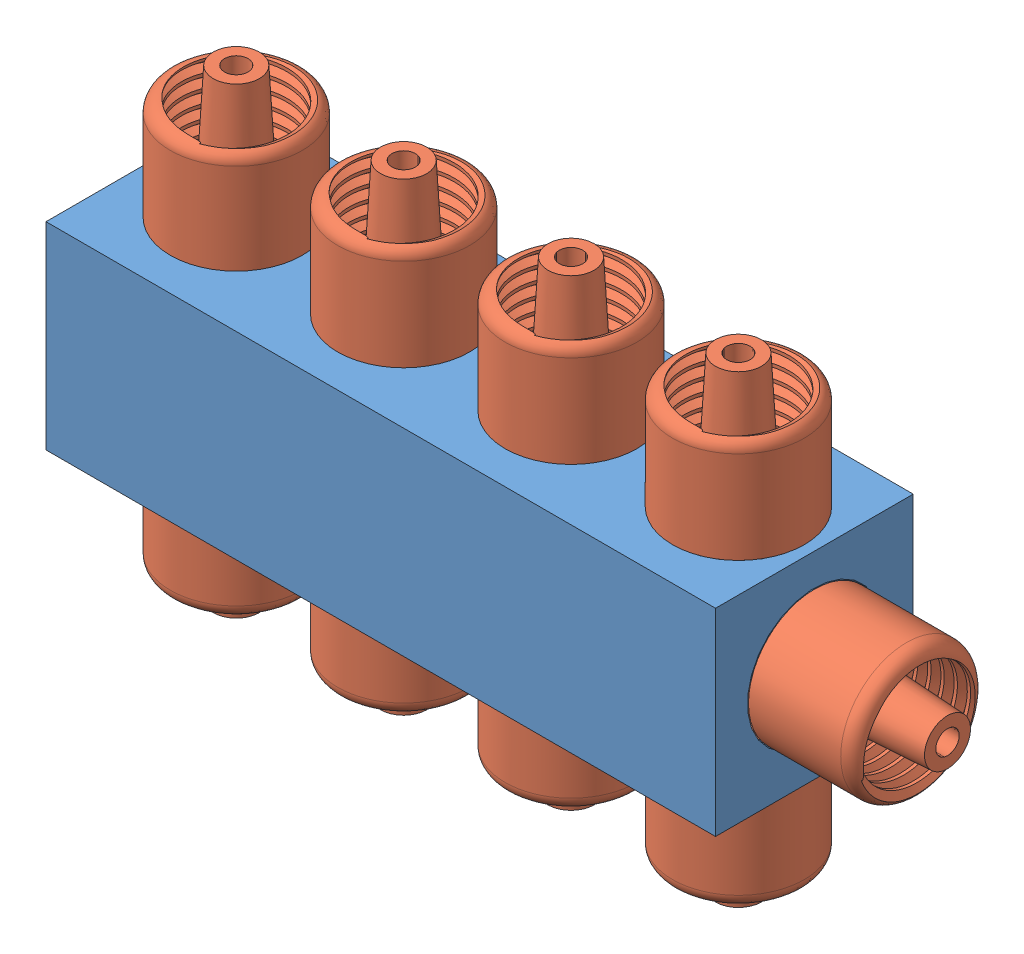
SolidWorks assembly valve_assembly, configuration Default. Lengths in mm.
Overall size (60.9 35.27 15).
10 component instances, 2 part files, 13 mates.
Components (placement in the parent):
- valve_connector-1: valve_connector [Default] at (38.3431 20.2317 33.0319) size (50.8 15 15)
- luer_lock-1: luer_lock [Default] at (32.5797 27.7739 33.0319) size (10 10.1 10)
- luer_lock-2: luer_lock [Default] at (-5.5203 27.6253 33.0319) size (10 10.1 10)
- luer_lock-3: luer_lock [Default] at (7.1797 27.7317 33.0319) size (10 10.1 10)
- luer_lock-4: luer_lock [Default] at (19.8797 27.7317 33.0319) size (10 10.1 10)
- luer_lock-6: luer_lock [Default] at (32.5797 12.7704 33.0319) x (0.999942 0 -0.010804) z (-0.010804 0 -0.999942) size (10 10.1 10)
- luer_lock-7: luer_lock [Default] at (19.8797 12.801 33.0319) x (1 0 0) z (0 0 -1) size (10 10.1 10)
- luer_lock-8: luer_lock [Default] at (7.1797 12.7007 33.0319) x (1 0 0) z (0 0 -1) size (10 10.1 10)
- luer_lock-9: luer_lock [Default] at (-5.5203 12.7317 33.0319) x (0.969422 0 0.2454) z (0.2454 0 -0.969422) size (10 10.1 10)
- luer_lock-10: luer_lock [Default] at (38.3431 20.2317 33.0319) x (0 -1 0) z (0 0 1) size (10 10.1 10)
Mates (geometry in assembly coordinates):
- Concentric1: concentric anti-aligned: circle of valve_connector-1; circle of luer_lock-1
- Concentric2: concentric anti-aligned: circle of valve_connector-1; circle of luer_lock-2
- Concentric3: concentric anti-aligned: circle of valve_connector-1; circle of luer_lock-3
- Concentric4: concentric anti-aligned: circle of valve_connector-1; circle of luer_lock-4
- Concentric8: concentric aligned: circle of valve_connector-1; circle of luer_lock-6
- Concentric9: concentric anti-aligned: cylinder of valve_connector-1; cylinder of luer_lock-6 through (32.5797 4.7704 33.0319) axis (0 1 0) radius 5
- Concentric10: concentric aligned: circle of valve_connector-1; circle of luer_lock-7
- Concentric11: concentric aligned: circle of valve_connector-1; circle of luer_lock-8
- Concentric13: concentric aligned: circle of valve_connector-1; circle of luer_lock-9
- Concentric16: concentric aligned: circle of valve_connector-1; circle of luer_lock-10
- Concentric17: concentric aligned: circle of valve_connector-1; circle of luer_lock-10
- Coincident1: coincident aligned: plane of valve_connector-1 through (38.3431 20.2317 33.0319) normal (1 0 0); circle of luer_lock-10
- Coincident2: coincident aligned: plane of valve_connector-1 through (-12.4569 12.7317 40.5319) normal (0 -1 0); circle of luer_lock-9
